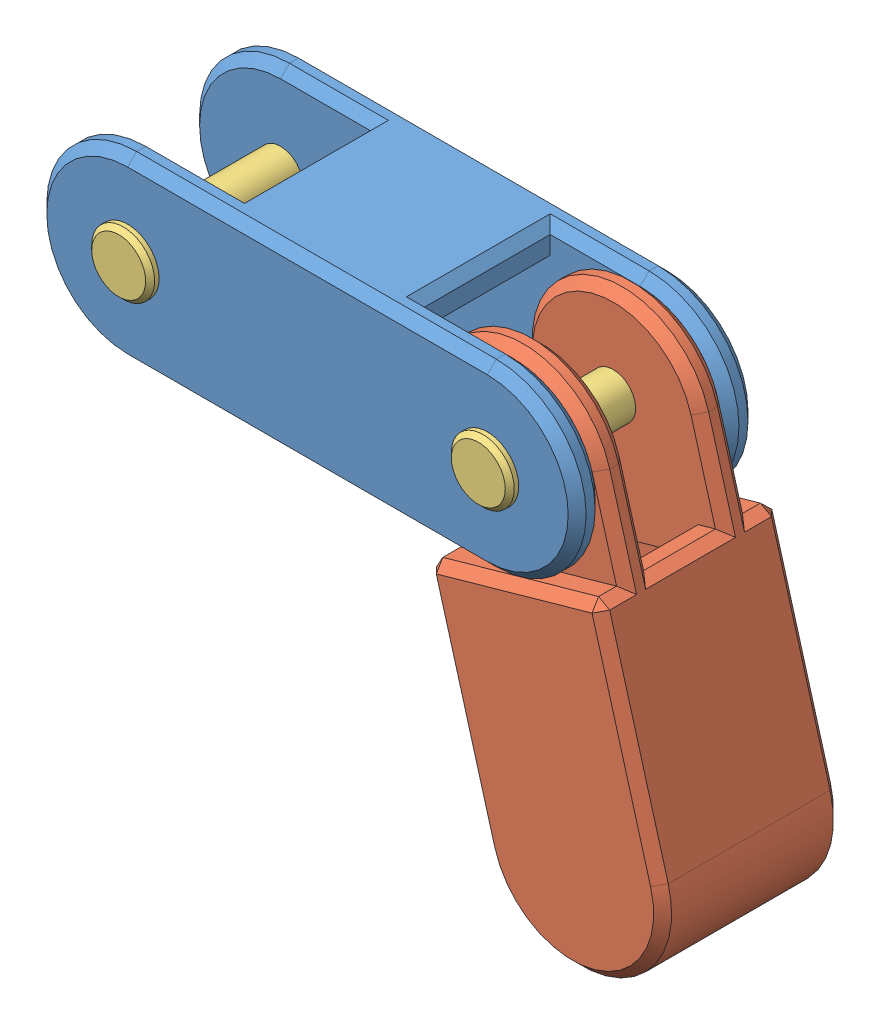
SolidWorks assembly Robot_Thumb, configuration Default. Lengths in mm.
Overall size (71.84 58.36 22).
4 component instances, 3 part files, 12 mates.
Components (placement in the parent):
- thumb_inner-1: thumb_inner [Default] at (20 0 0) size (60 20 20)
- thumb_top-1: thumb_top [Default] at (44.7524 -16.8423 0) x (0.271566 -0.96242 0) z (0 0 1) size (55 20 20)
- finger_connector-1: finger_connector [Default] at origin size (7 7 22)
- finger_connector-2: finger_connector [Default] at (40 0 0) x (0.271566 -0.96242 0) z (0 0 1) size (7 7 22)
Mates (geometry in assembly coordinates):
- Coincident1: coincident: plane of finger_connector-1 through (0 0 0) normal (0 0 1); plane of assembly through (0 0 0) normal (0 0 1)
- Coincident2: coincident: plane of finger_connector-1 through (0 0 0) normal (0 1 0); plane of assembly through (0 0 0) normal (0 1 0)
- Coincident3: coincident: plane of finger_connector-1 through (0 0 0) normal (1 0 0); plane of assembly through (0 0 0) normal (1 0 0)
- Concentric1: concentric: cylinder of thumb_inner-1 through (0 0 -10) axis (0 0 1) radius 2.5; cylinder of finger_connector-1 through (0 0 10) axis (0 0 -1) radius 2.5
- Coincident4: coincident: plane of thumb_inner-1 through (0 0 10) normal (0 0 1); plane of finger_connector-1 through (0 0 10) normal (0 0 -1)
- Coincident5: coincident: plane of thumb_inner-1 through (20 0 0) normal (0 1 0); plane of finger_connector-1 through (0 0 0) normal (0 1 0)
- Concentric2: concentric: cylinder of thumb_inner-1 through (40 0 -10) axis (0 0 1) radius 2.5; cylinder of finger_connector-2 through (40 0 10) axis (0 0 -1) radius 2.5
- Coincident6: coincident: plane of thumb_inner-1 through (0 0 10) normal (0 0 1); plane of finger_connector-2 through (40 0 10) normal (0 0 -1)
- Coincident7: coincident: plane of thumb_top-1; plane of finger_connector-2
- Concentric3: concentric: cylinder of thumb_top-1 through (40 0 -10) axis (0 0 1) radius 2.5; cylinder of finger_connector-2 through (40 0 10) axis (0 0 -1) radius 2.5
- Coincident8: coincident: plane of thumb_top-1 through (44.7524 -16.8423 0) normal (0 0 1); plane of finger_connector-2 through (40 0 0) normal (0 0 1)
- LimitAngle1: limit planar angle = 1.295777 rad: plane of finger_connector-2; plane of assembly through (0 0 0) normal (1 0 0)
